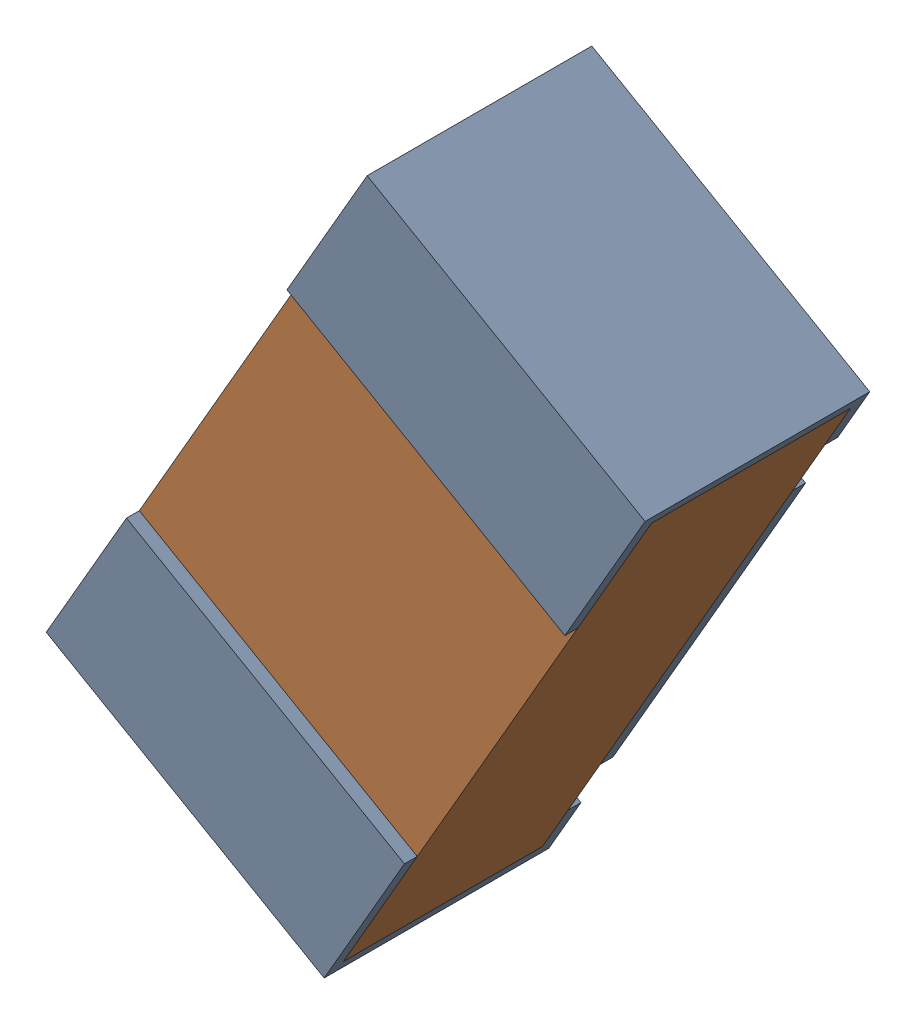
SolidWorks assembly R11, configuration Default. Lengths in mm.
Overall size (0.93 1.12 0.35).
3 component instances, 2 part files, 0 mates.
Components (placement in the parent):
- R11-subassembly-1-1: R11-subassembly-1 [Default] at (-5.2836 1.375 -1.6307) x (0.5 0.866025 0) z (-0.866025 0.5 0) size (1 0.35 0.5)
  - 0402 resistor-1: 0402 resistor [Default] at origin size (1 0.35 0.5)
  - 0402 resistor-1-1: 0402 resistor-1 [Default] at origin size (0.96 0.31 0.5)
